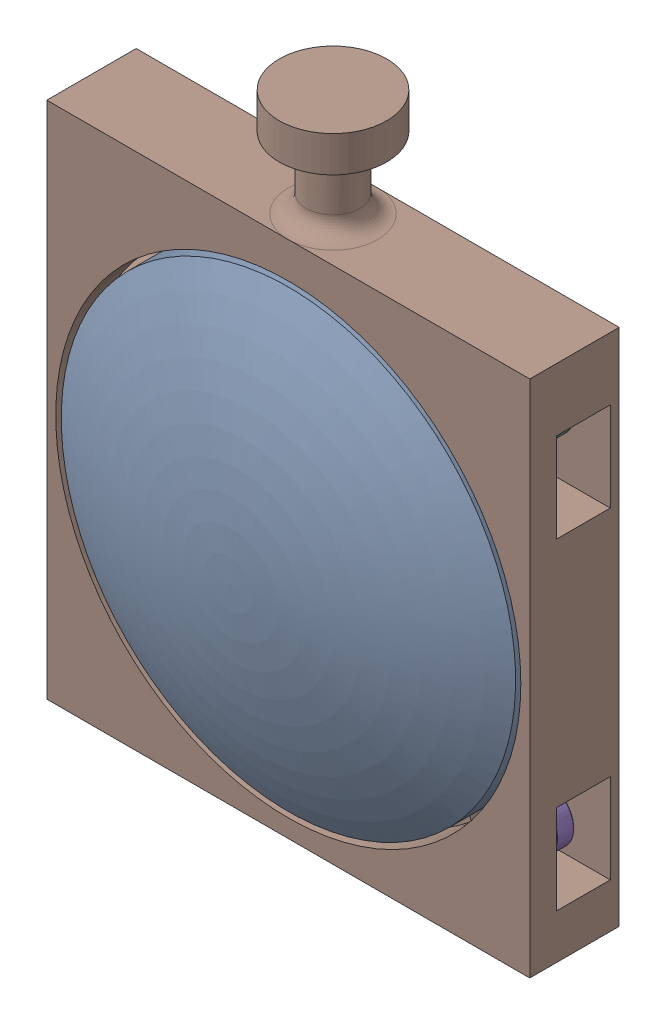
SolidWorks assembly assembly_collimator_openSIM_V2.0, configuration Default. Lengths in mm.
Overall size (27 35 8.84).
8 component instances, 3 part files, 2 mates.
Components (placement in the parent):
- LA1131-lens_50_openSIM_V2.0-1: LA1131-lens_50_openSIM_V2.0 [Default] at (13.5 13.5 5.67) x (0.99943 -0.033748 0) z (0 0 1) size (25.4 25.4 5.34)
- HXN3_1_openSIM_V2.0-1: HXN3_1_openSIM_V2.0 [Default] at (3.5 23.5 0.5) x (0 0 1) z (-0.23992 0.970793 0) size (1 3 3)
- HXN3_1_openSIM_V2.0-2: HXN3_1_openSIM_V2.0 [Default] at (23.5 23.5 0.5) x (0 0 1) z (-0.23992 0.970793 0) size (1 3 3)
- HXN3_1_openSIM_V2.0-4: HXN3_1_openSIM_V2.0 [Default] at (3.5 3.5 0.5) x (0 0 1) z (-0.23992 0.970793 0) size (1 3 3)
- HXN3_1_openSIM_V2.0-5: HXN3_1_openSIM_V2.0 [Default] at (23.5 3.5 0.5) x (0 0 1) z (-0.23992 0.970793 0) size (1 3 3)
- HXN3_1_openSIM_V2.0-6: HXN3_1_openSIM_V2.0 [Default] at (3.5 1.5 2.5) x (0 -1 0) z (-0.188264 0 0.982118) size (1 3 3)
- HXN3_1_openSIM_V2.0-7: HXN3_1_openSIM_V2.0 [Default] at (23.5 1.5 2.5) x (0 -1 0) z (-0.23992 0 0.970793) size (1 3 3)
- collimator_lens_holder_openSIM_V2.0-1: collimator_lens_holder_openSIM_V2.0 [Default] at (0 -0.5 0) size (27 35 6)
Mates (geometry in assembly coordinates):
- Coincident1: coincident: plane of LA1131-lens_50_20200728-1 through (13.5 13.5 3) normal (0 0 -1); plane of collimator_lens_holder_20200724_ER-1 through (13.5 13.5 3) normal (0 0 1)
- Concentric1: concentric aligned: circle of LA1131-lens_50_20200728-1; circle of collimator_lens_holder_20200724_ER-1
